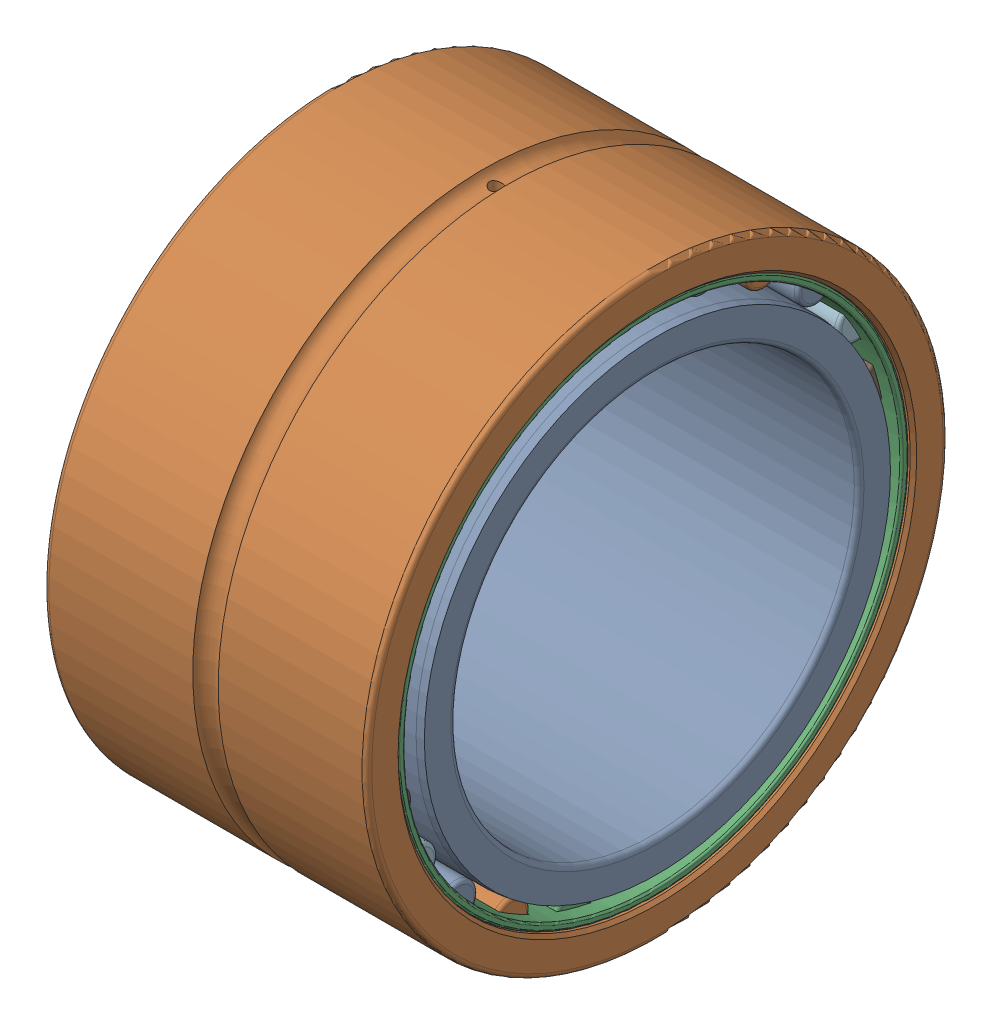
SolidWorks assembly NA6910R, configuration Default. Lengths in mm.
Overall size (40 72 72).
52 component instances, 4 part files, 0 mates.
Components (placement in the parent):
- NA6910RInner ring-1: NA6910RInner ring [Default] at origin size (40 58 58)
- NA6910ROuter ring-1: NA6910ROuter ring [Default] at origin size (40 72 72)
- NA6910RCage-1: NA6910RCage [Default] at (40 0 0) x (-1 0 0) z (0 0 -1) size (18.8 63.36 63.36)
- NA6910R ring-1: NA6910R ring [Default] at (2.4 31.275 0) size (15 4.55 4.55)
- NA6910R ring-2: NA6910R ring [Default] at (2.4 30.2093 8.0946) size (15 4.55 4.55)
- NA6910R ring-3: NA6910R ring [Default] at (2.4 27.0849 15.6375) size (15 4.55 4.55)
- NA6910R ring-4: NA6910R ring [Default] at (2.4 22.1148 22.1148) size (15 4.55 4.55)
- NA6910R ring-5: NA6910R ring [Default] at (2.4 15.6375 27.0849) size (15 4.55 4.55)
- NA6910R ring-6: NA6910R ring [Default] at (2.4 8.0946 30.2093) size (15 4.55 4.55)
- NA6910R ring-7: NA6910R ring [Default] at (2.4 0 31.275) size (15 4.55 4.55)
- NA6910R ring-8: NA6910R ring [Default] at (2.4 -8.0946 30.2093) size (15 4.55 4.55)
- NA6910R ring-9: NA6910R ring [Default] at (2.4 -15.6375 27.0849) size (15 4.55 4.55)
- NA6910R ring-10: NA6910R ring [Default] at (2.4 -22.1148 22.1148) size (15 4.55 4.55)
- NA6910R ring-11: NA6910R ring [Default] at (2.4 -27.0849 15.6375) size (15 4.55 4.55)
- NA6910R ring-12: NA6910R ring [Default] at (2.4 -30.2093 8.0946) size (15 4.55 4.55)
- NA6910R ring-13: NA6910R ring [Default] at (2.4 -31.275 0) size (15 4.55 4.55)
- NA6910R ring-14: NA6910R ring [Default] at (2.4 -30.2093 -8.0946) size (15 4.55 4.55)
- NA6910R ring-15: NA6910R ring [Default] at (2.4 -27.0849 -15.6375) size (15 4.55 4.55)
- NA6910R ring-16: NA6910R ring [Default] at (2.4 -22.1148 -22.1148) size (15 4.55 4.55)
- NA6910R ring-17: NA6910R ring [Default] at (2.4 -15.6375 -27.0849) size (15 4.55 4.55)
- NA6910R ring-18: NA6910R ring [Default] at (2.4 -8.0946 -30.2093) size (15 4.55 4.55)
- NA6910R ring-19: NA6910R ring [Default] at (2.4 0 -31.275) size (15 4.55 4.55)
- NA6910R ring-20: NA6910R ring [Default] at (2.4 8.0946 -30.2093) size (15 4.55 4.55)
- NA6910R ring-21: NA6910R ring [Default] at (2.4 15.6375 -27.0849) size (15 4.55 4.55)
- NA6910R ring-22: NA6910R ring [Default] at (2.4 22.1148 -22.1148) size (15 4.55 4.55)
- NA6910R ring-23: NA6910R ring [Default] at (2.4 27.0849 -15.6375) size (15 4.55 4.55)
- NA6910R ring-24: NA6910R ring [Default] at (2.4 30.2093 -8.0946) size (15 4.55 4.55)
- NA6910R ring-25: NA6910R ring [Default] at (22.6 31.275 0) size (15 4.55 4.55)
- NA6910R ring-26: NA6910R ring [Default] at (22.6 30.2093 8.0946) size (15 4.55 4.55)
- NA6910R ring-27: NA6910R ring [Default] at (22.6 27.0849 15.6375) size (15 4.55 4.55)
- NA6910R ring-28: NA6910R ring [Default] at (22.6 22.1148 22.1148) size (15 4.55 4.55)
- NA6910R ring-29: NA6910R ring [Default] at (22.6 15.6375 27.0849) size (15 4.55 4.55)
- NA6910R ring-30: NA6910R ring [Default] at (22.6 8.0946 30.2093) size (15 4.55 4.55)
- NA6910R ring-31: NA6910R ring [Default] at (22.6 0 31.275) size (15 4.55 4.55)
- NA6910R ring-32: NA6910R ring [Default] at (22.6 -8.0946 30.2093) size (15 4.55 4.55)
- NA6910R ring-33: NA6910R ring [Default] at (22.6 -15.6375 27.0849) size (15 4.55 4.55)
- NA6910R ring-34: NA6910R ring [Default] at (22.6 -22.1148 22.1148) size (15 4.55 4.55)
- NA6910R ring-35: NA6910R ring [Default] at (22.6 -27.0849 15.6375) size (15 4.55 4.55)
- NA6910R ring-36: NA6910R ring [Default] at (22.6 -30.2093 8.0946) size (15 4.55 4.55)
- NA6910R ring-37: NA6910R ring [Default] at (22.6 -31.275 0) size (15 4.55 4.55)
- NA6910R ring-38: NA6910R ring [Default] at (22.6 -30.2093 -8.0946) size (15 4.55 4.55)
- NA6910R ring-39: NA6910R ring [Default] at (22.6 -27.0849 -15.6375) size (15 4.55 4.55)
- NA6910R ring-40: NA6910R ring [Default] at (22.6 -22.1148 -22.1148) size (15 4.55 4.55)
- NA6910R ring-41: NA6910R ring [Default] at (22.6 -15.6375 -27.0849) size (15 4.55 4.55)
- NA6910R ring-42: NA6910R ring [Default] at (22.6 -8.0946 -30.2093) size (15 4.55 4.55)
- NA6910R ring-43: NA6910R ring [Default] at (22.6 0 -31.275) size (15 4.55 4.55)
- NA6910R ring-44: NA6910R ring [Default] at (22.6 8.0946 -30.2093) size (15 4.55 4.55)
- NA6910R ring-45: NA6910R ring [Default] at (22.6 15.6375 -27.0849) size (15 4.55 4.55)
- NA6910R ring-46: NA6910R ring [Default] at (22.6 22.1148 -22.1148) size (15 4.55 4.55)
- NA6910R ring-47: NA6910R ring [Default] at (22.6 27.0849 -15.6375) size (15 4.55 4.55)
- NA6910R ring-48: NA6910R ring [Default] at (22.6 30.2093 -8.0946) size (15 4.55 4.55)
- NA6910RCage-2: NA6910RCage [Default] at origin size (18.8 63.36 63.36)
